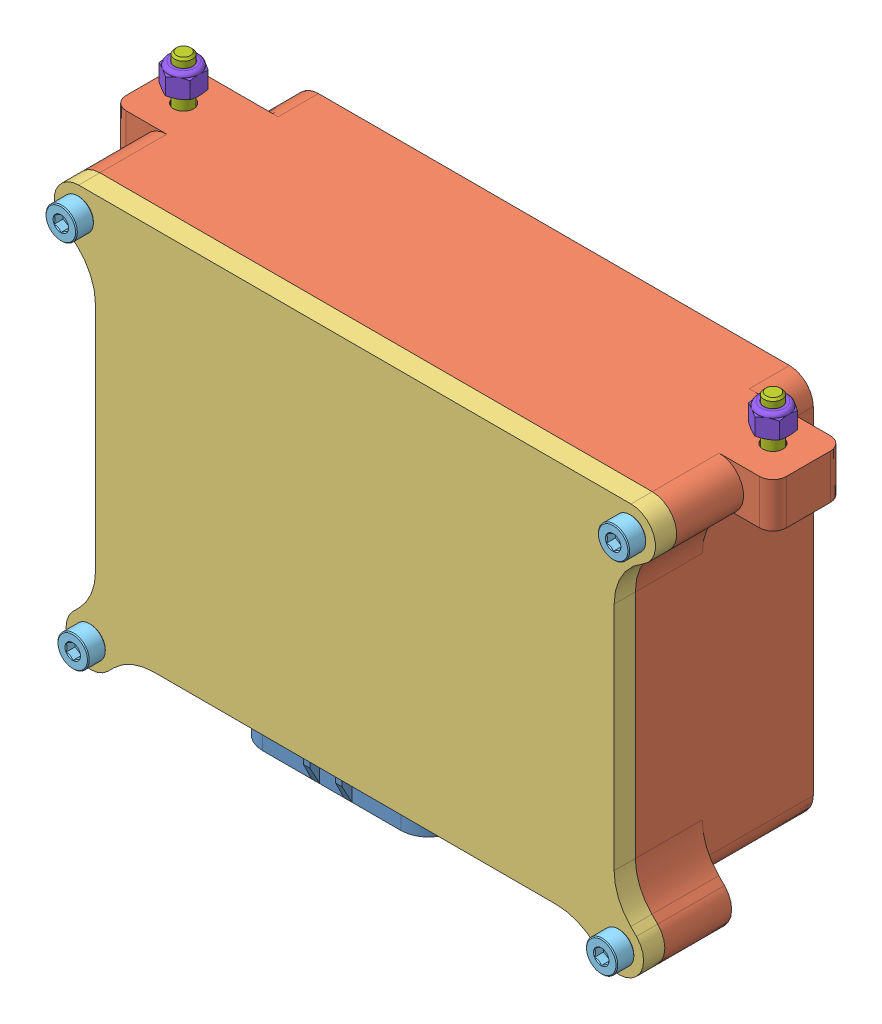
SolidWorks assembly EL-A0108-AA-Rear Telemnode Assembly, configuration Default. Lengths in mm.
Overall size (148.11 110.83 48.86).
23 component instances, 8 part files, 37 mates.
Components (placement in the parent):
- EL-80101-AA-Rear Telemnode PCB-1: EL-80101-AA-Rear Telemnode PCB [Default] at (74.1293 -58.4828 4.5975) x (0 1 0) z (0 0 1) size (84.08 96.37 32.1)
- EL-50100-AA-Rear Telemnode Enclosure-1: EL-50100-AA-Rear Telemnode Enclosure [Default] at origin size (148.11 92.81 39.92)
- EL-60102-AA-Telemnode Enclosure Lid-1: EL-60102-AA-Telemnode Enclosure Lid [Default] at (0 0 34.925) size (134.93 92.81 4.76)
- AC-Heat Set Insert, M4x7-4.7 (94180A351)-1: AC-Heat Set Insert, M4x7-4.7 (94180A351) [94180A351] at (61.9639 37.6 32.575) size (6.35 6.35 4.7)
- AC-Heat Set Insert, M4x7-4.7 (94180A351)-2: AC-Heat Set Insert, M4x7-4.7 (94180A351) [94180A351] at (59.2937 -44.2125 32.575) size (6.35 6.35 4.7)
- AC-Heat Set Insert, M4x7-4.7 (94180A351)-5: AC-Heat Set Insert, M4x7-4.7 (94180A351) [94180A351] at (29.0253 19.6412 0.65) x (0.996181 -0.087311 0) z (0 0 1) size (6.35 6.35 4.7)
- AC-Heat Set Insert, M4x7-4.7 (94180A351)-6: AC-Heat Set Insert, M4x7-4.7 (94180A351) [94180A351] at (29.0253 -8.2988 0.65) x (0.996181 -0.087311 0) z (0 0 1) size (6.35 6.35 4.7)
- AC-Heat Set Insert, M4x7-4.7 (94180A351)-7: AC-Heat Set Insert, M4x7-4.7 (94180A351) [94180A351] at (-42.7107 18.7332 0.65) x (0.996181 -0.087311 0) z (0 0 1) size (6.35 6.35 4.7)
- AC-Heat Set Insert, M4x7-4.7 (94180A351)-8: AC-Heat Set Insert, M4x7-4.7 (94180A351) [94180A351] at (-42.7107 -7.1748 0.65) x (0.996181 -0.087311 0) z (0 0 1) size (6.35 6.35 4.7)
- BR-Black Oxide C12.9 SHCS, M4x0.7-8 (91290A140)-1: BR-Black Oxide C12.9 SHCS, M4x0.7-8 (91290A140) [91290A140] at (61.9639 37.6 37.6875) size (7 7 12.17)
- BR-Black Oxide C12.9 SHCS, M4x0.7-8 (91290A140)-2: BR-Black Oxide C12.9 SHCS, M4x0.7-8 (91290A140) [91290A140] at (59.2937 -44.2125 37.6875) size (7 7 12.17)
- BR-Black Oxide C12.9 SHCS, M4x0.7-5 (91290A138)-1: BR-Black Oxide C12.9 SHCS, M4x0.7-5 (91290A138) [91290A138] at (29.0253 19.6412 4.5) x (0.025613 -0.999672 0) z (0 0 1) size (7 7 9.17)
- BR-Black Oxide C12.9 SHCS, M4x0.7-5 (91290A138)-2: BR-Black Oxide C12.9 SHCS, M4x0.7-5 (91290A138) [91290A138] at (29.0253 -8.2988 4.5) x (0.025613 -0.999672 0) z (0 0 1) size (7 7 9.17)
- BR-Black Oxide C12.9 SHCS, M4x0.7-5 (91290A138)-4: BR-Black Oxide C12.9 SHCS, M4x0.7-5 (91290A138) [91290A138] at (-42.7107 -7.1748 4.5) x (-0.169903 -0.985461 0) z (0 0 1) size (7 7 9.17)
- BR-Black Oxide C12.9 SHCS, M4x0.7-5 (91290A138)-5: BR-Black Oxide C12.9 SHCS, M4x0.7-5 (91290A138) [91290A138] at (-42.7107 18.7332 4.5) x (-0.169903 -0.985461 0) z (0 0 1) size (7 7 9.17)
- 91290A168_Alloy Steel Socket Head Screw M4x0.7, 20mm-1: 91290A168_Alloy Steel Socket Head Screw M4x0.7, 20mm [91290A168] at (66.1188 41.1 11.9875) x (1 0 0) z (0 -1 0) size (7 7 24.04)
- BR-Steel Nylon Locknut, Grade 8, M4x0.7 (90576A103)-1: BR-Steel Nylon Locknut, Grade 8, M4x0.7 (90576A103) [90576A103] at (66.1188 48.775 11.9875) x (1 0 0) z (0 1 0) size (7 8.08 5)
- BR-Steel Nylon Locknut, Grade 8, M4x0.7 (90576A103)-2: BR-Steel Nylon Locknut, Grade 8, M4x0.7 (90576A103) [90576A103] at (-66.1188 48.775 11.9875) x (1 0 0) z (0 1 0) size (7 8.08 5)
- 91290A168_Alloy Steel Socket Head Screw M4x0.7, 20mm-2: 91290A168_Alloy Steel Socket Head Screw M4x0.7, 20mm [91290A168] at (-66.1188 41.1 11.9875) x (1 0 0) z (0 -1 0) size (7 7 24.04)
- AC-Heat Set Insert, M4x7-4.7 (94180A351)-9: AC-Heat Set Insert, M4x7-4.7 (94180A351) [94180A351] at (-61.9639 37.6 32.575) x (1 0 0) z (0 0 -1) size (6.35 6.35 4.7)
- BR-Black Oxide C12.9 SHCS, M4x0.7-8 (91290A140)-3: BR-Black Oxide C12.9 SHCS, M4x0.7-8 (91290A140) [91290A140] at (-61.9639 37.6 37.6875) size (7 7 12.17)
- BR-Black Oxide C12.9 SHCS, M4x0.7-8 (91290A140)-4: BR-Black Oxide C12.9 SHCS, M4x0.7-8 (91290A140) [91290A140] at (-59.2937 -44.2125 37.6875) size (7 7 12.17)
- AC-Heat Set Insert, M4x7-4.7 (94180A351)-10: AC-Heat Set Insert, M4x7-4.7 (94180A351) [94180A351] at (-59.2937 -44.2125 32.575) x (1 0 0) z (0 0 -1) size (6.35 6.35 4.7)
Mates (geometry in assembly coordinates):
- Coincident1: coincident aligned: plane of Rear Telemnode Enclosure-1 through (0 0 0) normal (0 0 1)
- Coincident2: coordinate: point of Rear Telemnode Enclosure-1
- Distance1: distance = 5.08 mm anti-aligned: plane of Rear Telemnode Enclosure-1 through (-53.1812 38.1 34.925) normal (1 0 0); plane of Rear Telemnode-1 through (-47.7907 -29.5268 3.0024) normal (-1 0 0)
- Coincident12: coincident aligned: plane of Rear Telemnode Enclosure-1 through (0 0 34.925) normal (0 0 1); plane of Telemnode Enclosure Lid-1 through (0 0 34.925) normal (0 0 1)
- Coincident13: coincident aligned: plane of Telemnode Enclosure Lid-1 through (0 0 34.925) normal (0 1 0)
- Coincident14: coincident aligned: plane of Telemnode Enclosure Lid-1 through (0 0 34.925) normal (1 0 0)
- Coincident16: coincident anti-aligned: plane of Rear Telemnode-1 through (18.8062 -38.1 19) normal (0 -1 0); plane of Rear Telemnode Enclosure-1 through (-53.1812 -38.1 34.925) normal (0 1 0)
- Distance3: distance = 3 mm anti-aligned: plane of Rear Telemnode-1 through (24.3063 -36.1 3) normal (0 0 -1); plane of Rear Telemnode Enclosure-1 through (0 0 0) normal (0 0 1)
- Distance4: distance = 13 mm anti-aligned: plane of Rear Telemnode-1 through (40.1812 -23.9 5.275) normal (1 0 0); plane of Rear Telemnode Enclosure-1 through (53.1812 38.1 34.925) normal (-1 0 0)
- Concentric1: concentric aligned: cylinder of Rear Telemnode Enclosure-1 through (61.9639 37.6 26.925) axis (0 0 1) radius 3.025; cylinder of AC-Heat Set Insert, M4x7-4.7 (94180A351)-1 through (61.9639 37.6 34.925) axis (0 0 1) radius 2
- Coincident17: coincident aligned: plane of Rear Telemnode Enclosure-1 through (0 0 34.925) normal (0 0 1); plane of AC-Heat Set Insert, M4x7-4.7 (94180A351)-1 through (61.9639 39.6 34.925) normal (0 0 1)
- Concentric2: concentric aligned: cylinder of Rear Telemnode Enclosure-1 through (59.2937 -44.2125 26.925) axis (0 0 1) radius 3.025; cylinder of AC-Heat Set Insert, M4x7-4.7 (94180A351)-2 through (59.2937 -44.2125 34.925) axis (0 0 1) radius 2
- Coincident18: coincident aligned: plane of Rear Telemnode Enclosure-1 through (0 0 34.925) normal (0 0 1); plane of AC-Heat Set Insert, M4x7-4.7 (94180A351)-2 through (59.2937 -42.2125 34.925) normal (0 0 1)
- Concentric5: concentric aligned: cylinder of Rear Telemnode Enclosure-1 through (29.0253 19.6412 -3) axis (0 0 1) radius 3.025; cylinder of AC-Heat Set Insert, M4x7-4.7 (94180A351)-5 through (29.0253 19.6412 3) axis (0 0 1) radius 2
- Coincident21: coincident aligned: plane of Rear Telemnode Enclosure-1 through (0 0 3) normal (0 0 1); plane of AC-Heat Set Insert, M4x7-4.7 (94180A351)-5 through (29.1999 21.6336 3) normal (0 0 1)
- Concentric6: concentric aligned: cylinder of Rear Telemnode Enclosure-1 through (29.0253 -8.2988 -3) axis (0 0 1) radius 3.025; cylinder of AC-Heat Set Insert, M4x7-4.7 (94180A351)-6 through (29.0253 -8.2988 3) axis (0 0 1) radius 2
- Coincident22: coincident aligned: plane of Rear Telemnode Enclosure-1 through (0 0 3) normal (0 0 1); plane of AC-Heat Set Insert, M4x7-4.7 (94180A351)-6 through (29.1999 -6.3064 3) normal (0 0 1)
- Concentric7: concentric aligned: circle of Rear Telemnode Enclosure-1; cylinder of AC-Heat Set Insert, M4x7-4.7 (94180A351)-7 through (-42.7107 18.7332 3) axis (0 0 1) radius 2
- Coincident23: coincident aligned: plane of Rear Telemnode Enclosure-1 through (0 0 3) normal (0 0 1); plane of AC-Heat Set Insert, M4x7-4.7 (94180A351)-7 through (-42.5361 20.7256 3) normal (0 0 1)
- Concentric8: concentric aligned: circle of Rear Telemnode Enclosure-1; cylinder of AC-Heat Set Insert, M4x7-4.7 (94180A351)-8 through (-42.7107 -7.1748 3) axis (0 0 1) radius 2
- Coincident24: coincident aligned: plane of Rear Telemnode Enclosure-1 through (0 0 3) normal (0 0 1); plane of AC-Heat Set Insert, M4x7-4.7 (94180A351)-8 through (-42.5361 -5.1824 3) normal (0 0 1)
- Concentric9: concentric anti-aligned: cylinder of AC-Heat Set Insert, M4x7-4.7 (94180A351)-1 through (61.9639 37.6 34.925) axis (0 0 1) radius 2; cylinder of BR-Black Oxide C12.9 SHCS, M4x0.7-8 (91290A140)-1 through (61.9639 37.6 31.6875) axis (0 0 -1) radius 2
- Coincident25: coincident anti-aligned: plane of Telemnode Enclosure Lid-1 through (-61.9639 37.6 39.6875) normal (0 0 1); plane of BR-Black Oxide C12.9 SHCS, M4x0.7-8 (91290A140)-1 through (61.9639 40.9 39.6875) normal (0 0 -1)
- Concentric10: concentric anti-aligned: cylinder of AC-Heat Set Insert, M4x7-4.7 (94180A351)-2 through (59.2937 -44.2125 34.925) axis (0 0 1) radius 2; cylinder of BR-Black Oxide C12.9 SHCS, M4x0.7-8 (91290A140)-2 through (59.2937 -44.2125 31.6875) axis (0 0 -1) radius 2
- Coincident26: coincident anti-aligned: plane of Telemnode Enclosure Lid-1 through (-61.9639 37.6 39.6875) normal (0 0 1); plane of BR-Black Oxide C12.9 SHCS, M4x0.7-8 (91290A140)-2 through (59.2937 -40.9125 39.6875) normal (0 0 -1)
- Concentric11: concentric anti-aligned: cylinder of AC-Heat Set Insert, M4x7-4.7 (94180A351)-5 through (29.0253 19.6412 3) axis (0 0 1) radius 2; cylinder of BR-Black Oxide C12.9 SHCS, M4x0.7-5 (91290A138)-1 through (29.0253 19.6412 0) axis (0 0 -1) radius 3.5
- Distance5: distance = 5 mm anti-aligned: plane of BR-Black Oxide C12.9 SHCS, M4x0.7-5 (91290A138)-1 through (32.3242 19.7257 5) normal (0 0 -1); plane of Rear Telemnode Enclosure-1 through (0 0 0) normal (0 0 1)
- Concentric12: concentric anti-aligned: cylinder of AC-Heat Set Insert, M4x7-4.7 (94180A351)-6 through (29.0253 -8.2988 3) axis (0 0 1) radius 2; cylinder of BR-Black Oxide C12.9 SHCS, M4x0.7-5 (91290A138)-2 through (29.0253 -8.2988 0) axis (0 0 -1) radius 2
- Coincident29: coincident aligned: plane of BR-Black Oxide C12.9 SHCS, M4x0.7-5 (91290A138)-1 through (32.3242 19.7257 9) normal (0 0 1); plane of BR-Black Oxide C12.9 SHCS, M4x0.7-5 (91290A138)-2 through (32.3242 -8.2143 9) normal (0 0 1)
- Concentric15: concentric anti-aligned: cylinder of AC-Heat Set Insert, M4x7-4.7 (94180A351)-8 through (-42.7107 -7.1748 3) axis (0 0 1) radius 2; cylinder of BR-Black Oxide C12.9 SHCS, M4x0.7-5 (91290A138)-4 through (-42.7107 -7.1748 0) axis (0 0 -1) radius 2
- Coincident36: coincident aligned: plane of BR-Black Oxide C12.9 SHCS, M4x0.7-5 (91290A138)-2 through (32.3242 -8.2143 9) normal (0 0 1); plane of BR-Black Oxide C12.9 SHCS, M4x0.7-5 (91290A138)-4 through (-39.4587 -7.7355 9) normal (0 0 1)
- Concentric16: concentric anti-aligned: cylinder of AC-Heat Set Insert, M4x7-4.7 (94180A351)-7 through (-42.7107 18.7332 3) axis (0 0 1) radius 2; cylinder of BR-Black Oxide C12.9 SHCS, M4x0.7-5 (91290A138)-5 through (-42.7107 18.7332 0) axis (0 0 -1) radius 2
- Coincident37: coincident aligned: plane of BR-Black Oxide C12.9 SHCS, M4x0.7-5 (91290A138)-4 through (-39.4587 -7.7355 9) normal (0 0 1); plane of BR-Black Oxide C12.9 SHCS, M4x0.7-5 (91290A138)-5 through (-39.4587 18.1725 9) normal (0 0 1)
- Concentric17: concentric anti-aligned: cylinder of Rear Telemnode Enclosure-1 through (66.1188 33.1 11.9875) axis (0 -1 0) radius 2.25; cylinder of 91290A168_Alloy Steel Socket Head Screw (1)-1 through (66.1188 53.1 11.9875) axis (0 1 0) radius 2
- Coincident38: coincident anti-aligned: plane of Rear Telemnode Enclosure-1 through (0 33.1 0) normal (0 -1 0); plane of 91290A168_Alloy Steel Socket Head Screw (1)-1 through (66.1188 33.1 15.2875) normal (0 1 0)
- Concentric18: concentric anti-aligned: cylinder of 91290A168_Alloy Steel Socket Head Screw (1)-1 through (66.1188 53.1 11.9875) axis (0 1 0) radius 2; cylinder of BR-Steel Nylon Locknut, Grade 8, M4x0.7 (90576A103)-1 through (66.1188 51.275 11.9875) axis (0 -1 0) radius 2
- Distance7: distance = 3.175 mm anti-aligned: plane of Rear Telemnode Enclosure-1 through (-53.1812 43.1 34.925) normal (0 1 0); plane of BR-Steel Nylon Locknut, Grade 8, M4x0.7 (90576A103)-1 through (66.1188 46.275 11.9875) normal (0 -1 0)
